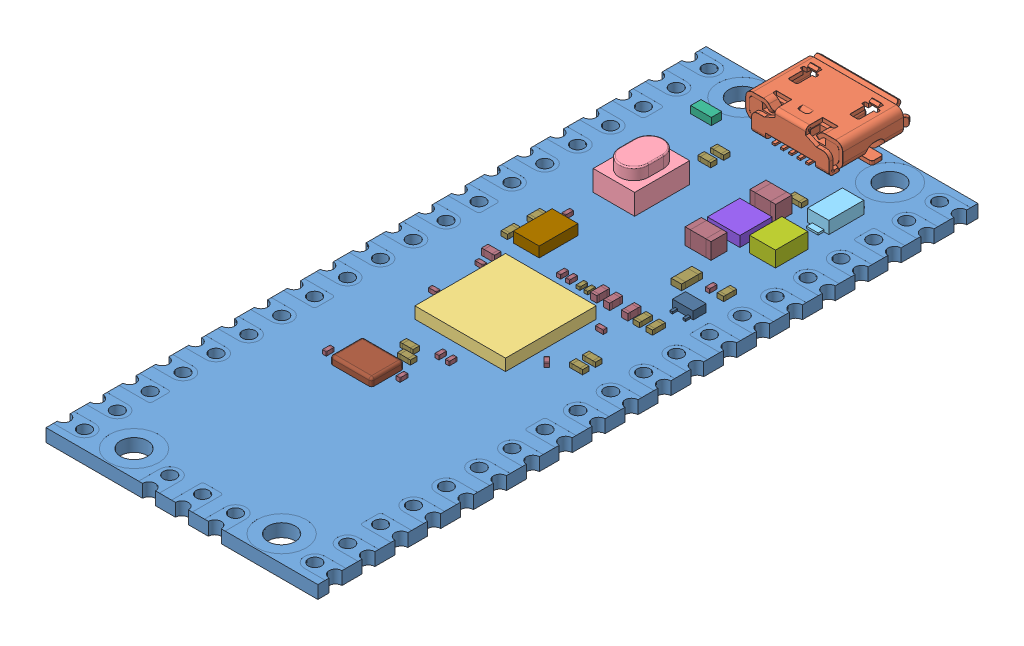
SolidWorks assembly Raspberry Pi Pico-R3, configuration Default. Lengths in mm.
Overall size (21 3.69 52.43).
44 component instances, 13 part files, 131 mates.
Components (placement in the parent):
- PCB, Raspberry Pi Pico-R3-1: PCB, Raspberry Pi Pico-R3 [Default] at origin size (21 1 51)
- MicroUSB Port, Raspberry Pi Pico-R3-1: MicroUSB Port, Raspberry Pi Pico-R3 [Default] at (0 0.5 -24.35) x (-1 0 0) z (0 0 -1) size (7.97 2.92 5.43)
- RP2040 Microcontroller, Raspberry Pi Pico-R3-1: RP2040 Microcontroller, Raspberry Pi Pico-R3 [Default] at (0 0.5 0.5) size (7 0.9 7)
- SW1, Tact Switch, Raspberry Pi Pico-R3-1: SW1, Tact Switch, Raspberry Pi Pico-R3 [Default] at (-3.5 0.5 -13.5) size (3.2 2.5 4.25)
- D1, Diode, Schottky, Raspberry Pi Pico-R3-1: D1, Diode, Schottky, Raspberry Pi Pico-R3 [Default] at (6 0.5 -19) size (1.65 0.95 3.6)
- D2, QSME-C194, LED, Raspberry Pi Pico-R3-1: D2, QSME-C194, LED, Raspberry Pi Pico-R3 [Default] at (-5.8 0.5 -20.8) size (1.6 0.55 0.8)
- L1, Inductor, Raspberry Pi Pico-R3-1: L1, Inductor, Raspberry Pi Pico-R3 [Default] at (6 0.5 -14.6) size (2 1.2 2.5)
- U2, RT6150B-33GQW, Buck Boost Converter, Raspberry Pi Pico-R3-1: U2, RT6150B-33GQW, Buck Boost Converter, Raspberry Pi Pico-R3 [Default] at (3 0.5 -14.6) size (2.5 0.8 2.5)
- U3, W25Q16JVUXIQ, Serial NOR Flash 16 Mbit, Raspberry Pi Pico-R3-1: U3, W25Q16JVUXIQ, Serial NOR Flash 16 Mbit, Raspberry Pi Pico-R3 [Default] at (-3.8 0.5 -6.4) size (2 0.8 3)
- Q1, MOSFET, DMG1012T, Raspberry Pi Pico-R3-1: Q1, MOSFET, DMG1012T, Raspberry Pi Pico-R3 [Default] at (6.5 0.5 -7.2) size (1.6 0.6 1.8)
- X1, X12M000000S096, 12 Mhz Crystal Resonator, Raspberry Pi Pico-R3-1: X1, X12M000000S096, 12 Mhz Crystal Resonator, Raspberry Pi Pico-R3 [Default] at (-2.2 0.5 9) size (3.2 0.6 2.5)
- SMD Resistor, Configurable, Raspberry Pi Pico-R3-1: SMD Resistor, Configurable, Raspberry Pi Pico-R3 [R1] at (6.2 0.5 1) x (0 0 -1) z (1 0 0) size (0.5 0.35 1)
- SMD Resistor, Configurable, Raspberry Pi Pico-R3-2: SMD Resistor, Configurable, Raspberry Pi Pico-R3 [R2] at (3.5 0.5 -18.6) x (0 0 -1) z (1 0 0) size (0.5 0.35 1)
- SMD Resistor, Configurable, Raspberry Pi Pico-R3-3: SMD Resistor, Configurable, Raspberry Pi Pico-R3 [R3] at (-2.7 0.5 -17.8) x (0 0 -1) z (1 0 0) size (0.5 0.35 1)
- SMD Resistor, Configurable, Raspberry Pi Pico-R3-4: SMD Resistor, Configurable, Raspberry Pi Pico-R3 [R4] at (-5.5 0.5 -5.4) x (-1 0 0) z (0 0 -1) size (0.5 0.35 1)
- SMD Resistor, Configurable, Raspberry Pi Pico-R3-5: SMD Resistor, Configurable, Raspberry Pi Pico-R3 [R5] at (7 0.5 -9.6) x (-1 0 0) z (0 0 -1) size (0.5 0.35 1)
- SMD Resistor, Configurable, Raspberry Pi Pico-R3-6: SMD Resistor, Configurable, Raspberry Pi Pico-R3 [R6] at (6.5 0.5 -4.6) x (-1 0 0) z (0 0 -1) size (0.5 0.35 1)
- SMD Resistor, Configurable, Raspberry Pi Pico-R3-7: SMD Resistor, Configurable, Raspberry Pi Pico-R3 [R7] at (4.5 0.5 -9) x (-1 0 0) z (0 0 -1) size (0.8 0.45 1.6)
- SMD Resistor, Configurable, Raspberry Pi Pico-R3-8: SMD Resistor, Configurable, Raspberry Pi Pico-R3 [R8] at (-2.7 0.5 -18.8) x (0 0 -1) z (1 0 0) size (0.5 0.35 1)
- SMD Resistor, Configurable, Raspberry Pi Pico-R3-9: SMD Resistor, Configurable, Raspberry Pi Pico-R3 [R9] at (5.5 0.5 -4.6) x (-1 0 0) z (0 0 -1) size (0.5 0.35 1)
- SMD Resistor, Configurable, Raspberry Pi Pico-R3-10: SMD Resistor, Configurable, Raspberry Pi Pico-R3 [R10] at (6.2 0.5 0) x (0 0 -1) z (1 0 0) size (0.5 0.35 1)
- SMD Resistor, Configurable, Raspberry Pi Pico-R3-11: SMD Resistor, Configurable, Raspberry Pi Pico-R3 [R11] at (-5.5 0.5 -7.4) size (0.5 0.35 1)
- SMD Resistor, Configurable, Raspberry Pi Pico-R3-12: SMD Resistor, Configurable, Raspberry Pi Pico-R3 [R12] at (0.8 0.5 -4.6) x (-1 0 0) z (0 0 -1) size (0.3 0.23 0.6)
- SMD Resistor, Configurable, Raspberry Pi Pico-R3-13: SMD Resistor, Configurable, Raspberry Pi Pico-R3 [R13] at (1.4 0.5 -4.6) x (-1 0 0) z (0 0 -1) size (0.3 0.23 0.6)
- SMD Resistor, Configurable, Raspberry Pi Pico-R3-14: SMD Resistor, Configurable, Raspberry Pi Pico-R3 [R14] at (-1.1 0.5 7) x (0 0 -1) z (1 0 0) size (0.5 0.35 1)
- SMD Resistor, Configurable, Raspberry Pi Pico-R3-15: SMD Resistor, Configurable, Raspberry Pi Pico-R3 [R15] at (-1.7 0.5 6.2) x (0 0 -1) z (1 0 0) size (0.5 0.35 1)
- SMD Capacitor, Configurable, Raspberry Pi Pico-R3-1: SMD Capacitor, Configurable, Raspberry Pi Pico-R3 [C1] at (3 0.5 -17) x (0 0 -1) z (1 0 0) size (1.25 1.25 2)
- SMD Capacitor, Configurable, Raspberry Pi Pico-R3-2: SMD Capacitor, Configurable, Raspberry Pi Pico-R3 [C2] at (3 0.5 -12) x (0 0 -1) z (1 0 0) size (1.25 1.25 2)
- SMD Capacitor, Configurable, Raspberry Pi Pico-R3-3: SMD Capacitor, Configurable, Raspberry Pi Pico-R3 [C3] at (6 0.5 -9.4) size (0.3 0.3 0.6)
- SMD Capacitor, Configurable, Raspberry Pi Pico-R3-4: SMD Capacitor, Configurable, Raspberry Pi Pico-R3 [C4] at (-4.5 0.5 -2.1) x (0 0 1) z (-1 0 0) size (0.3 0.3 0.6)
- SMD Capacitor, Configurable, Raspberry Pi Pico-R3-5: SMD Capacitor, Configurable, Raspberry Pi Pico-R3 [C5] at (-4.5 0.5 1.5) x (0 0 1) z (-1 0 0) size (0.3 0.3 0.6)
- SMD Capacitor, Configurable, Raspberry Pi Pico-R3-6: SMD Capacitor, Configurable, Raspberry Pi Pico-R3 [C6] at (4.6 0.5 1.9) x (0.707107 0 -0.707107) z (0.707107 0 0.707107) size (0.3 0.3 0.6)
- SMD Capacitor, Configurable, Raspberry Pi Pico-R3-7: SMD Capacitor, Configurable, Raspberry Pi Pico-R3 [C7] at (4.5 0.5 -2.4) x (0 0 1) z (-1 0 0) size (0.3 0.3 0.6)
- SMD Capacitor, Configurable, Raspberry Pi Pico-R3-8: SMD Capacitor, Configurable, Raspberry Pi Pico-R3 [C8] at (0 0.5 5.5) size (0.3 0.3 0.6)
- SMD Capacitor, Configurable, Raspberry Pi Pico-R3-9: SMD Capacitor, Configurable, Raspberry Pi Pico-R3 [C9] at (0.8 0.5 5.5) size (0.3 0.3 0.6)
- SMD Capacitor, Configurable, Raspberry Pi Pico-R3-10: SMD Capacitor, Configurable, Raspberry Pi Pico-R3 [C10] at (0 0.5 -4.6) size (0.3 0.3 0.6)
- SMD Capacitor, Configurable, Raspberry Pi Pico-R3-11: SMD Capacitor, Configurable, Raspberry Pi Pico-R3 [C11] at (-0.7 0.5 -4.6) size (0.3 0.3 0.6)
- SMD Capacitor, Configurable, Raspberry Pi Pico-R3-19: SMD Capacitor, Configurable, Raspberry Pi Pico-R3 [C12] at (2.2 0.5 -4.6) size (0.5 0.5 1)
- SMD Capacitor, Configurable, Raspberry Pi Pico-R3-20: SMD Capacitor, Configurable, Raspberry Pi Pico-R3 [C13] at (4.6 0.5 -4.6) size (0.5 0.5 1)
- SMD Capacitor, Configurable, Raspberry Pi Pico-R3-21: SMD Capacitor, Configurable, Raspberry Pi Pico-R3 [C14] at (3.2 0.5 -4.6) size (0.5 0.5 1)
- SMD Capacitor, Configurable, Raspberry Pi Pico-R3-22: SMD Capacitor, Configurable, Raspberry Pi Pico-R3 [C15] at (-4.5 0.5 -8.8) size (0.3 0.3 0.6)
- SMD Capacitor, Configurable, Raspberry Pi Pico-R3-23: SMD Capacitor, Configurable, Raspberry Pi Pico-R3 [C16] at (-4.6 0.5 9.6) size (0.3 0.3 0.6)
- SMD Capacitor, Configurable, Raspberry Pi Pico-R3-24: SMD Capacitor, Configurable, Raspberry Pi Pico-R3 [C17] at (0 0.5 8.5) size (0.3 0.3 0.6)
- SMD Capacitor, Configurable, Raspberry Pi Pico-R3-18: SMD Capacitor, Configurable, Raspberry Pi Pico-R3 [C18] at (-4.7 0.5 -3.1) x (0 0 1) z (-1 0 0) size (0.5 0.5 1)
Mates (geometry in assembly coordinates):
- Coincident1: coordinate: point of PCB, Raspberry Pi Pico-R3-1
- Coincident2: coincident anti-aligned: plane of MicroUSB Port, Raspberry Pi Pico-R3-1 through (0 0.5 -24.35) normal (-1 0 0); plane of assembly through (0 0 0) normal (1 0 0)
- Coincident4: coincident aligned: plane of PCB, Raspberry Pi Pico-R3-1 through (0 0.5 0) normal (0 1 0); plane of MicroUSB Port, Raspberry Pi Pico-R3-1 through (0 0.5 -24.35) normal (0 1 0)
- Distance1: distance anti-aligned: plane of PCB, Raspberry Pi Pico-R3-1 through (-10.5 -0.5 -25.5) normal (0 0 -1); plane of MicroUSB Port, Raspberry Pi Pico-R3-1 through (-1.2 2.0268 -21.5) normal (0 0 1)
- Coincident5: coincident anti-aligned: plane of PCB, Raspberry Pi Pico-R3-1 through (0 0.5 0) normal (0 1 0); plane of RP2040 Microcontroller, Raspberry Pi Pico-R3-1 through (0 0.5 0.5) normal (0 -1 0)
- Coincident6: coincident aligned: plane of RP2040 Microcontroller, Raspberry Pi Pico-R3-1 through (0 0.5 0.5) normal (1 0 0); plane of assembly through (0 0 0) normal (1 0 0)
- Coincident7: coincident anti-aligned: plane of PCB, Raspberry Pi Pico-R3-1 through (0 0.5 0) normal (0 1 0); plane of SW1, Tact Switch, Raspberry Pi Pico-R3-1 through (-3.5 0.5 -13.5) normal (0 -1 0)
- Distance2: distance = 3.5 mm aligned: plane of SW1, Tact Switch, Raspberry Pi Pico-R3-1 through (-3.5 0.5 -13.5) normal (1 0 0); plane of assembly through (0 0 0) normal (1 0 0)
- Distance3: distance = 13.5 mm: plane of assembly through (0 0 0) normal (0 0 1); plane of assembly; plane of SW1, Tact Switch, Raspberry Pi Pico-R3-1 through (-3.5 0.5 -13.5) normal (0 0 1)
- Coincident8: coincident anti-aligned: plane of PCB, Raspberry Pi Pico-R3-1 through (0 0.5 0) normal (0 1 0); plane of D1, Diode, Schottky, Raspberry Pi Pico-R3-1 through (6 0.5 -19) normal (0 -1 0)
- Distance4: distance = 6 mm aligned: plane of D1, Diode, Schottky, Raspberry Pi Pico-R3-1 through (6 0.5 -19) normal (1 0 0); plane of assembly through (0 0 0) normal (1 0 0)
- Distance5: distance = 19 mm: plane of assembly through (0 0 0) normal (0 0 1); plane of assembly; plane of D1, Diode, Schottky, Raspberry Pi Pico-R3-1 through (6 0.5 -19) normal (0 0 1)
- Coincident9: coincident anti-aligned: plane of PCB, Raspberry Pi Pico-R3-1 through (0 0.5 0) normal (0 1 0); plane of L1, Inductor, Raspberry Pi Pico-R3-1 through (6 0.5 -14.6) normal (0 -1 0)
- Coincident10: coincident aligned: plane of D1, Diode, Schottky, Raspberry Pi Pico-R3-1 through (6 0.5 -19) normal (1 0 0); plane of L1, Inductor, Raspberry Pi Pico-R3-1 through (6 0.5 -14.6) normal (1 0 0)
- Distance6: distance = 4.4 mm aligned: plane of L1, Inductor, Raspberry Pi Pico-R3-1 through (6 0.5 -14.6) normal (0 0 1); plane of D1, Diode, Schottky, Raspberry Pi Pico-R3-1 through (6 0.5 -19) normal (0 0 1)
- Coincident11: coincident anti-aligned: plane of PCB, Raspberry Pi Pico-R3-1 through (0 0.5 0) normal (0 1 0); plane of SMD Resistor, Configurable, Raspberry Pi Pico-R3-1 through (6.2 0.5 1) normal (0 -1 0)
- Distance8: distance = 6.2 mm aligned: plane of SMD Resistor, Configurable, Raspberry Pi Pico-R3-1 through (6.2 0.5 1) normal (1 0 0); plane of assembly through (0 0 0) normal (1 0 0)
- Distance9: distance = 1 mm anti-aligned: plane of SMD Resistor, Configurable, Raspberry Pi Pico-R3-1 through (6.2 0.5 1) normal (0 0 -1); plane of assembly through (0 0 0) normal (0 0 1)
- Coincident13: coincident anti-aligned: plane of PCB, Raspberry Pi Pico-R3-1 through (0 0.5 0) normal (0 1 0); plane of SMD Resistor, Configurable, Raspberry Pi Pico-R3-2 through (3.5 0.5 -18.6) normal (0 -1 0)
- Distance10: distance = 3.5 mm aligned: plane of SMD Resistor, Configurable, Raspberry Pi Pico-R3-2 through (3.5 0.5 -18.6) normal (1 0 0); plane of assembly through (0 0 0) normal (1 0 0)
- Distance11: distance = 18.6 mm anti-aligned: plane of SMD Resistor, Configurable, Raspberry Pi Pico-R3-2 through (3.5 0.5 -18.6) normal (0 0 -1); plane of assembly through (0 0 0) normal (0 0 1)
- Coincident14: coincident anti-aligned: plane of PCB, Raspberry Pi Pico-R3-1 through (0 0.5 0) normal (0 1 0); plane of SMD Resistor, Configurable, Raspberry Pi Pico-R3-3 through (-2.7 0.5 -17.8) normal (0 -1 0)
- Coincident15: coincident anti-aligned: plane of PCB, Raspberry Pi Pico-R3-1 through (0 0.5 0) normal (0 1 0); plane of SMD Resistor, Configurable, Raspberry Pi Pico-R3-4 through (-5.5 0.5 -5.4) normal (0 -1 0)
- Coincident16: coincident anti-aligned: plane of PCB, Raspberry Pi Pico-R3-1 through (0 0.5 0) normal (0 1 0); plane of SMD Resistor, Configurable, Raspberry Pi Pico-R3-5 through (7 0.5 -9.6) normal (0 -1 0)
- Coincident17: coincident anti-aligned: plane of PCB, Raspberry Pi Pico-R3-1 through (0 0.5 0) normal (0 1 0); plane of SMD Resistor, Configurable, Raspberry Pi Pico-R3-6 through (6.5 0.5 -4.6) normal (0 -1 0)
- Coincident18: coincident anti-aligned: plane of PCB, Raspberry Pi Pico-R3-1 through (0 0.5 0) normal (0 1 0); plane of SMD Resistor, Configurable, Raspberry Pi Pico-R3-7 through (4.5 0.5 -9) normal (0 -1 0)
- Coincident19: coincident anti-aligned: plane of PCB, Raspberry Pi Pico-R3-1 through (0 0.5 0) normal (0 1 0); plane of SMD Resistor, Configurable, Raspberry Pi Pico-R3-8 through (-2.7 0.5 -18.8) normal (0 -1 0)
- Coincident20: coincident anti-aligned: plane of PCB, Raspberry Pi Pico-R3-1 through (0 0.5 0) normal (0 1 0); plane of SMD Resistor, Configurable, Raspberry Pi Pico-R3-9 through (5.5 0.5 -4.6) normal (0 -1 0)
- Coincident21: coincident anti-aligned: plane of PCB, Raspberry Pi Pico-R3-1 through (0 0.5 0) normal (0 1 0); plane of SMD Resistor, Configurable, Raspberry Pi Pico-R3-10 through (6.2 0.5 0) normal (0 -1 0)
- Coincident22: coincident anti-aligned: plane of PCB, Raspberry Pi Pico-R3-1 through (0 0.5 0) normal (0 1 0); plane of SMD Resistor, Configurable, Raspberry Pi Pico-R3-11 through (-5.5 0.5 -7.4) normal (0 -1 0)
- Coincident23: coincident anti-aligned: plane of PCB, Raspberry Pi Pico-R3-1 through (0 0.5 0) normal (0 1 0); plane of SMD Resistor, Configurable, Raspberry Pi Pico-R3-12 through (0.8 0.5 -4.6) normal (0 -1 0)
- Coincident24: coincident anti-aligned: plane of PCB, Raspberry Pi Pico-R3-1 through (0 0.5 0) normal (0 1 0); plane of SMD Resistor, Configurable, Raspberry Pi Pico-R3-13 through (1.4 0.5 -4.6) normal (0 -1 0)
- Coincident25: coincident anti-aligned: plane of PCB, Raspberry Pi Pico-R3-1 through (0 0.5 0) normal (0 1 0); plane of SMD Resistor, Configurable, Raspberry Pi Pico-R3-14 through (-1.1 0.5 7) normal (0 -1 0)
- Coincident26: coincident anti-aligned: plane of PCB, Raspberry Pi Pico-R3-1 through (0 0.5 0) normal (0 1 0); plane of SMD Resistor, Configurable, Raspberry Pi Pico-R3-15 through (-1.7 0.5 6.2) normal (0 -1 0)
- Distance12: distance = 2.7 mm aligned: plane of SMD Resistor, Configurable, Raspberry Pi Pico-R3-3 through (-2.7 0.5 -17.8) normal (1 0 0); plane of assembly through (0 0 0) normal (1 0 0)
- Coincident27: coincident aligned: plane of SMD Resistor, Configurable, Raspberry Pi Pico-R3-3 through (-2.7 0.5 -17.8) normal (1 0 0); plane of SMD Resistor, Configurable, Raspberry Pi Pico-R3-8 through (-2.7 0.5 -18.8) normal (1 0 0)
- Distance14: distance = 1 mm aligned: plane of SMD Resistor, Configurable, Raspberry Pi Pico-R3-3 through (-2.7 0.5 -17.8) normal (0 0 -1); plane of SMD Resistor, Configurable, Raspberry Pi Pico-R3-8 through (-2.7 0.5 -18.8) normal (0 0 -1)
- Distance15: distance = 17.8 mm anti-aligned: plane of SMD Resistor, Configurable, Raspberry Pi Pico-R3-3 through (-2.7 0.5 -17.8) normal (0 0 -1); plane of assembly through (0 0 0) normal (0 0 1)
- Coincident28: coincident anti-aligned: plane of SMD Resistor, Configurable, Raspberry Pi Pico-R3-4 through (-5.5 0.5 -5.4) normal (-1 0 0); plane of SMD Resistor, Configurable, Raspberry Pi Pico-R3-11 through (-5.5 0.5 -7.4) normal (1 0 0)
- Distance16: distance = 5.5 mm: plane of assembly through (0 0 0) normal (1 0 0); plane of assembly; plane of SMD Resistor, Configurable, Raspberry Pi Pico-R3-4 through (-5.5 0.5 -5.4) normal (-1 0 0)
- Distance17: distance = 5.4 mm anti-aligned: plane of SMD Resistor, Configurable, Raspberry Pi Pico-R3-4 through (-5.5 0.5 -5.4) normal (0 0 -1); plane of assembly through (0 0 0) normal (0 0 1)
- Distance18: distance = 2 mm anti-aligned: plane of SMD Resistor, Configurable, Raspberry Pi Pico-R3-4 through (-5.5 0.5 -5.4) normal (0 0 -1); plane of SMD Resistor, Configurable, Raspberry Pi Pico-R3-11 through (-5.5 0.5 -7.4) normal (0 0 1)
- Distance19: distance = 4.5 mm anti-aligned: plane of SMD Resistor, Configurable, Raspberry Pi Pico-R3-7 through (4.5 0.5 -9) normal (-1 0 0); plane of assembly through (0 0 0) normal (1 0 0)
- Distance20: distance = 9 mm anti-aligned: plane of SMD Resistor, Configurable, Raspberry Pi Pico-R3-7 through (4.5 0.5 -9) normal (0 0 -1); plane of assembly through (0 0 0) normal (0 0 1)
- Distance21: distance = 7 mm anti-aligned: plane of SMD Resistor, Configurable, Raspberry Pi Pico-R3-5 through (7 0.5 -9.6) normal (-1 0 0); plane of assembly through (0 0 0) normal (1 0 0)
- Distance22: distance = 9.6 mm anti-aligned: plane of SMD Resistor, Configurable, Raspberry Pi Pico-R3-5 through (7 0.5 -9.6) normal (0 0 -1); plane of assembly through (0 0 0) normal (0 0 1)
- Coincident29: coincident aligned: plane of SMD Resistor, Configurable, Raspberry Pi Pico-R3-6 through (6.5 0.5 -4.6) normal (0 0 -1); plane of SMD Resistor, Configurable, Raspberry Pi Pico-R3-9 through (5.5 0.5 -4.6) normal (0 0 -1)
- Distance23: distance = 6.5 mm anti-aligned: plane of SMD Resistor, Configurable, Raspberry Pi Pico-R3-6 through (6.5 0.5 -4.6) normal (-1 0 0); plane of assembly through (0 0 0) normal (1 0 0)
- Distance24: distance = 1 mm aligned: plane of SMD Resistor, Configurable, Raspberry Pi Pico-R3-9 through (5.5 0.5 -4.6) normal (-1 0 0); plane of SMD Resistor, Configurable, Raspberry Pi Pico-R3-6 through (6.5 0.5 -4.6) normal (-1 0 0)
- Coincident30: coincident aligned: plane of SMD Resistor, Configurable, Raspberry Pi Pico-R3-1 through (6.2 0.5 1) normal (1 0 0); plane of SMD Resistor, Configurable, Raspberry Pi Pico-R3-10 through (6.2 0.5 0) normal (1 0 0)
- Distance25: distance = 1 mm aligned: plane of SMD Resistor, Configurable, Raspberry Pi Pico-R3-1 through (6.2 0.5 1) normal (0 0 -1); plane of SMD Resistor, Configurable, Raspberry Pi Pico-R3-10 through (6.2 0.5 0) normal (0 0 -1)
- Distance26: distance = 0.8 mm anti-aligned: plane of SMD Resistor, Configurable, Raspberry Pi Pico-R3-12 through (0.8 0.5 -4.6) normal (-1 0 0); plane of assembly through (0 0 0) normal (1 0 0)
- Distance27: distance = 0.6 mm aligned: plane of SMD Resistor, Configurable, Raspberry Pi Pico-R3-13 through (1.4 0.5 -4.6) normal (-1 0 0); plane of SMD Resistor, Configurable, Raspberry Pi Pico-R3-12 through (0.8 0.5 -4.6) normal (-1 0 0)
- Coincident31: coincident aligned: plane of SMD Resistor, Configurable, Raspberry Pi Pico-R3-12 through (0.8 0.5 -4.6) normal (0 0 -1); plane of SMD Resistor, Configurable, Raspberry Pi Pico-R3-13 through (1.4 0.5 -4.6) normal (0 0 -1)
- Distance28: distance = 4.6 mm anti-aligned: plane of SMD Resistor, Configurable, Raspberry Pi Pico-R3-12 through (0.8 0.5 -4.6) normal (0 0 -1); plane of assembly through (0 0 0) normal (0 0 1)
- Distance29: distance = 0.6 mm aligned: plane of SMD Resistor, Configurable, Raspberry Pi Pico-R3-14 through (-1.1 0.5 7) normal (1 0 0); plane of SMD Resistor, Configurable, Raspberry Pi Pico-R3-15 through (-1.7 0.5 6.2) normal (1 0 0)
- Distance30: distance = 0.8 mm aligned: plane of SMD Resistor, Configurable, Raspberry Pi Pico-R3-14 through (-1.1 0.5 7) normal (0 0 -1); plane of SMD Resistor, Configurable, Raspberry Pi Pico-R3-15 through (-1.7 0.5 6.2) normal (0 0 -1)
- Distance31: distance = 7 mm anti-aligned: plane of SMD Resistor, Configurable, Raspberry Pi Pico-R3-14 through (-1.1 0.5 7) normal (0 0 -1); plane of assembly through (0 0 0) normal (0 0 1)
- Distance32: distance = 4.6 mm anti-aligned: plane of SMD Resistor, Configurable, Raspberry Pi Pico-R3-9 through (5.5 0.5 -4.6) normal (0 0 -1); plane of assembly through (0 0 0) normal (0 0 1)
- Distance33: distance = 0.5 mm aligned: plane of RP2040 Microcontroller, Raspberry Pi Pico-R3-1 through (0 0.5 0.5) normal (0 0 1); plane of assembly through (0 0 0) normal (0 0 1)
- Distance34: distance = 1.1 mm aligned: plane of SMD Resistor, Configurable, Raspberry Pi Pico-R3-14 through (-1.1 0.5 7) normal (1 0 0); plane of assembly through (0 0 0) normal (1 0 0)
- Coincident32: coincident anti-aligned: plane of PCB, Raspberry Pi Pico-R3-1 through (0 0.5 0) normal (0 1 0); plane of SMD Capacitor, Configurable, Raspberry Pi Pico-R3-1 through (3 0.5 -17) normal (0 -1 0)
- Coincident33: coincident anti-aligned: plane of PCB, Raspberry Pi Pico-R3-1 through (0 0.5 0) normal (0 1 0); plane of SMD Capacitor, Configurable, Raspberry Pi Pico-R3-2 through (3 0.5 -12) normal (0 -1 0)
- Coincident34: coincident anti-aligned: plane of PCB, Raspberry Pi Pico-R3-1 through (0 0.5 0) normal (0 1 0); plane of SMD Capacitor, Configurable, Raspberry Pi Pico-R3-3 through (6 0.5 -9.4) normal (0 -1 0)
- Coincident35: coincident anti-aligned: plane of PCB, Raspberry Pi Pico-R3-1 through (0 0.5 0) normal (0 1 0); plane of SMD Capacitor, Configurable, Raspberry Pi Pico-R3-18 through (-4.7 0.5 -3.1) normal (0 -1 0)
- Coincident36: coincident anti-aligned: plane of PCB, Raspberry Pi Pico-R3-1 through (0 0.5 0) normal (0 1 0); plane of SMD Capacitor, Configurable, Raspberry Pi Pico-R3-10 through (0 0.5 -4.6) normal (0 -1 0)
- Coincident37: coincident anti-aligned: plane of PCB, Raspberry Pi Pico-R3-1 through (0 0.5 0) normal (0 1 0); plane of SMD Capacitor, Configurable, Raspberry Pi Pico-R3-9 through (0.8 0.5 5.5) normal (0 -1 0)
- Coincident38: coincident anti-aligned: plane of PCB, Raspberry Pi Pico-R3-1 through (0 0.5 0) normal (0 1 0); plane of SMD Capacitor, Configurable, Raspberry Pi Pico-R3-8 through (0 0.5 5.5) normal (0 -1 0)
- Coincident39: coincident anti-aligned: plane of PCB, Raspberry Pi Pico-R3-1 through (0 0.5 0) normal (0 1 0); plane of SMD Capacitor, Configurable, Raspberry Pi Pico-R3-7 through (4.5 0.5 -2.4) normal (0 -1 0)
- Coincident40: coincident anti-aligned: plane of PCB, Raspberry Pi Pico-R3-1 through (0 0.5 0) normal (0 1 0); plane of SMD Capacitor, Configurable, Raspberry Pi Pico-R3-6 through (4.6 0.5 1.9) normal (0 -1 0)
- Coincident41: coincident anti-aligned: plane of PCB, Raspberry Pi Pico-R3-1 through (0 0.5 0) normal (0 1 0); plane of SMD Capacitor, Configurable, Raspberry Pi Pico-R3-5 through (-4.5 0.5 1.5) normal (0 -1 0)
- Coincident42: coincident anti-aligned: plane of PCB, Raspberry Pi Pico-R3-1 through (0 0.5 0) normal (0 1 0); plane of SMD Capacitor, Configurable, Raspberry Pi Pico-R3-4 through (-4.5 0.5 -2.1) normal (0 -1 0)
- Coincident43: coincident anti-aligned: plane of PCB, Raspberry Pi Pico-R3-1 through (0 0.5 0) normal (0 1 0); plane of SMD Capacitor, Configurable, Raspberry Pi Pico-R3-11 through (-0.7 0.5 -4.6) normal (0 -1 0)
- Coincident44: coincident anti-aligned: plane of PCB, Raspberry Pi Pico-R3-1 through (0 0.5 0) normal (0 1 0); plane of SMD Capacitor, Configurable, Raspberry Pi Pico-R3-19 through (2.2 0.5 -4.6) normal (0 -1 0)
- Coincident45: coincident anti-aligned: plane of PCB, Raspberry Pi Pico-R3-1 through (0 0.5 0) normal (0 1 0); plane of SMD Capacitor, Configurable, Raspberry Pi Pico-R3-20 through (4.6 0.5 -4.6) normal (0 -1 0)
- Coincident46: coincident anti-aligned: plane of PCB, Raspberry Pi Pico-R3-1 through (0 0.5 0) normal (0 1 0); plane of SMD Capacitor, Configurable, Raspberry Pi Pico-R3-21 through (3.2 0.5 -4.6) normal (0 -1 0)
- Coincident47: coincident anti-aligned: plane of PCB, Raspberry Pi Pico-R3-1 through (0 0.5 0) normal (0 1 0); plane of SMD Capacitor, Configurable, Raspberry Pi Pico-R3-22 through (-4.5 0.5 -8.8) normal (0 -1 0)
- Coincident48: coincident anti-aligned: plane of PCB, Raspberry Pi Pico-R3-1 through (0 0.5 0) normal (0 1 0); plane of SMD Capacitor, Configurable, Raspberry Pi Pico-R3-23 through (-4.6 0.5 9.6) normal (0 -1 0)
- Coincident49: coincident anti-aligned: plane of PCB, Raspberry Pi Pico-R3-1 through (0 0.5 0) normal (0 1 0); plane of SMD Capacitor, Configurable, Raspberry Pi Pico-R3-24 through (0 0.5 8.5) normal (0 -1 0)
- Coincident50: coincident aligned: plane of SMD Capacitor, Configurable, Raspberry Pi Pico-R3-1 through (3 0.5 -17) normal (1 0 0); plane of SMD Capacitor, Configurable, Raspberry Pi Pico-R3-2 through (3 0.5 -12) normal (1 0 0)
- Distance35: distance = 3 mm aligned: plane of SMD Capacitor, Configurable, Raspberry Pi Pico-R3-1 through (3 0.5 -17) normal (1 0 0); plane of assembly through (0 0 0) normal (1 0 0)
- Distance36: distance = 17 mm anti-aligned: plane of SMD Capacitor, Configurable, Raspberry Pi Pico-R3-1 through (3 0.5 -17) normal (0 0 -1); plane of assembly through (0 0 0) normal (0 0 1)
- Distance37: distance = 12 mm anti-aligned: plane of SMD Capacitor, Configurable, Raspberry Pi Pico-R3-2 through (3 0.5 -12) normal (0 0 -1); plane of assembly through (0 0 0) normal (0 0 1)
- Distance38: distance = 4.5 mm aligned: plane of SMD Capacitor, Configurable, Raspberry Pi Pico-R3-22 through (-4.5 0.5 -8.8) normal (1 0 0); plane of assembly through (0 0 0) normal (1 0 0)
- Distance39: distance = 8.8 mm aligned: plane of SMD Capacitor, Configurable, Raspberry Pi Pico-R3-22 through (-4.5 0.5 -8.8) normal (0 0 1); plane of assembly through (0 0 0) normal (0 0 1)
- Distance40: distance = 4.6 mm aligned: plane of SMD Capacitor, Configurable, Raspberry Pi Pico-R3-23 through (-4.6 0.5 9.6) normal (1 0 0); plane of assembly through (0 0 0) normal (1 0 0)
- Distance41: distance = 9.6 mm aligned: plane of SMD Capacitor, Configurable, Raspberry Pi Pico-R3-23 through (-4.6 0.5 9.6) normal (0 0 1); plane of assembly through (0 0 0) normal (0 0 1)
- Distance42: distance = 0 mm aligned: plane of SMD Capacitor, Configurable, Raspberry Pi Pico-R3-24 through (0 0.5 8.5) normal (1 0 0); plane of assembly through (0 0 0) normal (1 0 0)
- Distance43: distance = 8.5 mm aligned: plane of SMD Capacitor, Configurable, Raspberry Pi Pico-R3-24 through (0 0.5 8.5) normal (0 0 1); plane of assembly through (0 0 0) normal (0 0 1)
- Distance44: distance = 1.5 mm aligned: plane of SMD Capacitor, Configurable, Raspberry Pi Pico-R3-5 through (-4.5 0.5 1.5) normal (0 0 1); plane of assembly through (0 0 0) normal (0 0 1)
- Distance45: distance = 4.5 mm anti-aligned: plane of SMD Capacitor, Configurable, Raspberry Pi Pico-R3-5 through (-4.5 0.5 1.5) normal (-1 0 0); plane of assembly through (0 0 0) normal (1 0 0)
- Coincident54: coincident aligned: plane of SMD Capacitor, Configurable, Raspberry Pi Pico-R3-4 through (-4.5 0.5 -2.1) normal (-1 0 0); plane of SMD Capacitor, Configurable, Raspberry Pi Pico-R3-5 through (-4.5 0.5 1.5) normal (-1 0 0)
- Distance46: distance = 3.6 mm aligned: plane of SMD Capacitor, Configurable, Raspberry Pi Pico-R3-4 through (-4.5 0.5 -2.1) normal (0 0 1); plane of SMD Capacitor, Configurable, Raspberry Pi Pico-R3-5 through (-4.5 0.5 1.5) normal (0 0 1)
- Coincident55: coincident aligned: plane of SMD Capacitor, Configurable, Raspberry Pi Pico-R3-8 through (0 0.5 5.5) normal (0 0 1); plane of SMD Capacitor, Configurable, Raspberry Pi Pico-R3-9 through (0.8 0.5 5.5) normal (0 0 1)
- Coincident56: coincident aligned: plane of SMD Capacitor, Configurable, Raspberry Pi Pico-R3-8 through (0 0.5 5.5) normal (1 0 0); plane of assembly through (0 0 0) normal (1 0 0)
- Distance47: distance = 0.8 mm aligned: plane of SMD Capacitor, Configurable, Raspberry Pi Pico-R3-9 through (0.8 0.5 5.5) normal (1 0 0); plane of SMD Capacitor, Configurable, Raspberry Pi Pico-R3-8 through (0 0.5 5.5) normal (1 0 0)
- Distance48: distance = 5.5 mm aligned: plane of SMD Capacitor, Configurable, Raspberry Pi Pico-R3-8 through (0 0.5 5.5) normal (0 0 1); plane of assembly through (0 0 0) normal (0 0 1)
- Distance49: distance = 4.7 mm anti-aligned: plane of SMD Capacitor, Configurable, Raspberry Pi Pico-R3-18 through (-4.7 0.5 -3.1) normal (-1 0 0); plane of assembly through (0 0 0) normal (1 0 0)
- Distance50: distance = 1 mm aligned: plane of SMD Capacitor, Configurable, Raspberry Pi Pico-R3-18 through (-4.7 0.5 -3.1) normal (0 0 1); plane of SMD Capacitor, Configurable, Raspberry Pi Pico-R3-4 through (-4.5 0.5 -2.1) normal (0 0 1)
- Distance51: distance = 4.5 mm anti-aligned: plane of SMD Capacitor, Configurable, Raspberry Pi Pico-R3-7 through (4.5 0.5 -2.4) normal (-1 0 0); plane of assembly through (0 0 0) normal (1 0 0)
- Distance52: distance = 2.4 mm aligned: plane of SMD Capacitor, Configurable, Raspberry Pi Pico-R3-7 through (4.5 0.5 -2.4) normal (0 0 1); plane of assembly through (0 0 0) normal (0 0 1)
- Angle1: planar angle = 0.785398 rad aligned: plane of SMD Capacitor, Configurable, Raspberry Pi Pico-R3-6 through (4.6 0.5 1.9) normal (0.707107 0 -0.707107); plane of assembly through (0 0 0) normal (1 0 0)
- Distance53: distance = 4.6 mm: unknown of SMD Capacitor, Configurable, Raspberry Pi Pico-R3-6
- Distance54: distance = 1.9 mm: unknown of SMD Capacitor, Configurable, Raspberry Pi Pico-R3-6
- Coincident61: coincident anti-aligned: plane of SMD Resistor, Configurable, Raspberry Pi Pico-R3-9 through (5.5 0.5 -4.6) normal (0 0 -1); plane of SMD Capacitor, Configurable, Raspberry Pi Pico-R3-20 through (4.6 0.5 -4.6) normal (0 0 1)
- Coincident62: coincident aligned: plane of SMD Capacitor, Configurable, Raspberry Pi Pico-R3-20 through (4.6 0.5 -4.6) normal (0 0 1); plane of SMD Capacitor, Configurable, Raspberry Pi Pico-R3-10 through (0 0.5 -4.6) normal (0 0 1)
- Coincident63: coincident aligned: plane of SMD Capacitor, Configurable, Raspberry Pi Pico-R3-20 through (4.6 0.5 -4.6) normal (0 0 1); plane of SMD Capacitor, Configurable, Raspberry Pi Pico-R3-11 through (-0.7 0.5 -4.6) normal (0 0 1)
- Coincident64: coincident aligned: plane of SMD Capacitor, Configurable, Raspberry Pi Pico-R3-20 through (4.6 0.5 -4.6) normal (0 0 1); plane of SMD Capacitor, Configurable, Raspberry Pi Pico-R3-19 through (2.2 0.5 -4.6) normal (0 0 1)
- Coincident65: coincident aligned: plane of SMD Capacitor, Configurable, Raspberry Pi Pico-R3-20 through (4.6 0.5 -4.6) normal (0 0 1); plane of SMD Capacitor, Configurable, Raspberry Pi Pico-R3-21 through (3.2 0.5 -4.6) normal (0 0 1)
- Distance55: distance = 4.6 mm aligned: plane of SMD Capacitor, Configurable, Raspberry Pi Pico-R3-20 through (4.6 0.5 -4.6) normal (1 0 0); plane of assembly through (0 0 0) normal (1 0 0)
- Distance56: distance = 3.2 mm aligned: plane of SMD Capacitor, Configurable, Raspberry Pi Pico-R3-21 through (3.2 0.5 -4.6) normal (1 0 0); plane of assembly through (0 0 0) normal (1 0 0)
- Distance57: distance = 2.2 mm aligned: plane of SMD Capacitor, Configurable, Raspberry Pi Pico-R3-19 through (2.2 0.5 -4.6) normal (1 0 0); plane of assembly through (0 0 0) normal (1 0 0)
- Coincident66: coincident aligned: plane of SMD Capacitor, Configurable, Raspberry Pi Pico-R3-10 through (0 0.5 -4.6) normal (1 0 0); plane of assembly through (0 0 0) normal (1 0 0)
- Distance58: distance = 0.7 mm aligned: plane of SMD Capacitor, Configurable, Raspberry Pi Pico-R3-11 through (-0.7 0.5 -4.6) normal (1 0 0); plane of assembly through (0 0 0) normal (1 0 0)
- Distance59: distance = 6 mm aligned: plane of SMD Capacitor, Configurable, Raspberry Pi Pico-R3-3 through (6 0.5 -9.4) normal (1 0 0); plane of assembly through (0 0 0) normal (1 0 0)
- Distance60: distance = 9.4 mm aligned: plane of SMD Capacitor, Configurable, Raspberry Pi Pico-R3-3 through (6 0.5 -9.4) normal (0 0 1); plane of assembly through (0 0 0) normal (0 0 1)
- Coincident67: coincident anti-aligned: plane of PCB, Raspberry Pi Pico-R3-1 through (0 0.5 0) normal (0 1 0); plane of U2, RT6150B-33GQW, Buck Boost Converter, Raspberry Pi Pico-R3-1 through (3 0.5 -14.6) normal (0 -1 0)
- Coincident68: coincident aligned: plane of SMD Capacitor, Configurable, Raspberry Pi Pico-R3-1 through (3 0.5 -17) normal (1 0 0); plane of U2, RT6150B-33GQW, Buck Boost Converter, Raspberry Pi Pico-R3-1 through (3 0.5 -14.6) normal (1 0 0)
- Distance61: distance = 14.6 mm aligned: plane of U2, RT6150B-33GQW, Buck Boost Converter, Raspberry Pi Pico-R3-1 through (3 0.5 -14.6) normal (0 0 1); plane of assembly through (0 0 0) normal (0 0 1)
- Coincident69: coincident anti-aligned: plane of PCB, Raspberry Pi Pico-R3-1 through (0 0.5 0) normal (0 1 0); plane of U3, W25Q16JVUXIQ, Serial NOR Flash 16 Mbit, Raspberry Pi Pico-R3-1 through (-3.8 0.5 -6.4) normal (0 -1 0)
- Distance62: distance = 3.8 mm aligned: plane of U3, W25Q16JVUXIQ, Serial NOR Flash 16 Mbit, Raspberry Pi Pico-R3-1 through (-3.8 0.5 -6.4) normal (1 0 0); plane of assembly through (0 0 0) normal (1 0 0)
- Distance63: distance = 6.4 mm aligned: plane of U3, W25Q16JVUXIQ, Serial NOR Flash 16 Mbit, Raspberry Pi Pico-R3-1 through (-3.8 0.5 -6.4) normal (0 0 1); plane of assembly through (0 0 0) normal (0 0 1)
- Coincident70: coincident anti-aligned: plane of PCB, Raspberry Pi Pico-R3-1 through (0 0.5 0) normal (0 1 0); plane of D2, QSME-C194, LED, Raspberry Pi Pico-R3-1 through (-5.8 0.5 -20.8) normal (0 -1 0)
- Distance64: distance = 5.8 mm aligned: plane of D2, QSME-C194, LED, Raspberry Pi Pico-R3-1 through (-5.8 0.5 -20.8) normal (1 0 0); plane of assembly through (0 0 0) normal (1 0 0)
- Distance65: distance = 20.8 mm aligned: plane of D2, QSME-C194, LED, Raspberry Pi Pico-R3-1 through (-5.8 0.5 -20.8) normal (0 0 1); plane of assembly through (0 0 0) normal (0 0 1)
- Coincident71: coincident anti-aligned: plane of PCB, Raspberry Pi Pico-R3-1 through (0 0.5 0) normal (0 1 0); plane of Q1, MOSFET, DMG1012T, Raspberry Pi Pico-R3-1 through (6.5 0.5 -7.2) normal (0 -1 0)
- Distance66: distance = 6.5 mm aligned: plane of Q1, MOSFET, DMG1012T, Raspberry Pi Pico-R3-1 through (6.5 0.5 -7.2) normal (1 0 0); plane of assembly through (0 0 0) normal (1 0 0)
- Distance67: distance = 7.2 mm aligned: plane of Q1, MOSFET, DMG1012T, Raspberry Pi Pico-R3-1 through (6.5 0.5 -7.2) normal (0 0 1); plane of assembly through (0 0 0) normal (0 0 1)
- Distance691: distance = 2.2 mm aligned: plane of X1, X12M000000S096, 12 Mhz Crystal Resonator, Raspberry Pi Pico-R3-1 through (-2.2 0.5 9) normal (1 0 0); plane of assembly through (0 0 0) normal (1 0 0)
- Distance701: distance = 9 mm aligned: plane of X1, X12M000000S096, 12 Mhz Crystal Resonator, Raspberry Pi Pico-R3-1 through (-2.2 0.5 9) normal (0 0 1); plane of assembly through (0 0 0) normal (0 0 1)
- Coincident72: coincident anti-aligned: plane of PCB, Raspberry Pi Pico-R3-1 through (0 0.5 0) normal (0 1 0); plane of X1, X12M000000S096, 12 Mhz Crystal Resonator, Raspberry Pi Pico-R3-1 through (-2.2 0.5 9) normal (0 -1 0)
